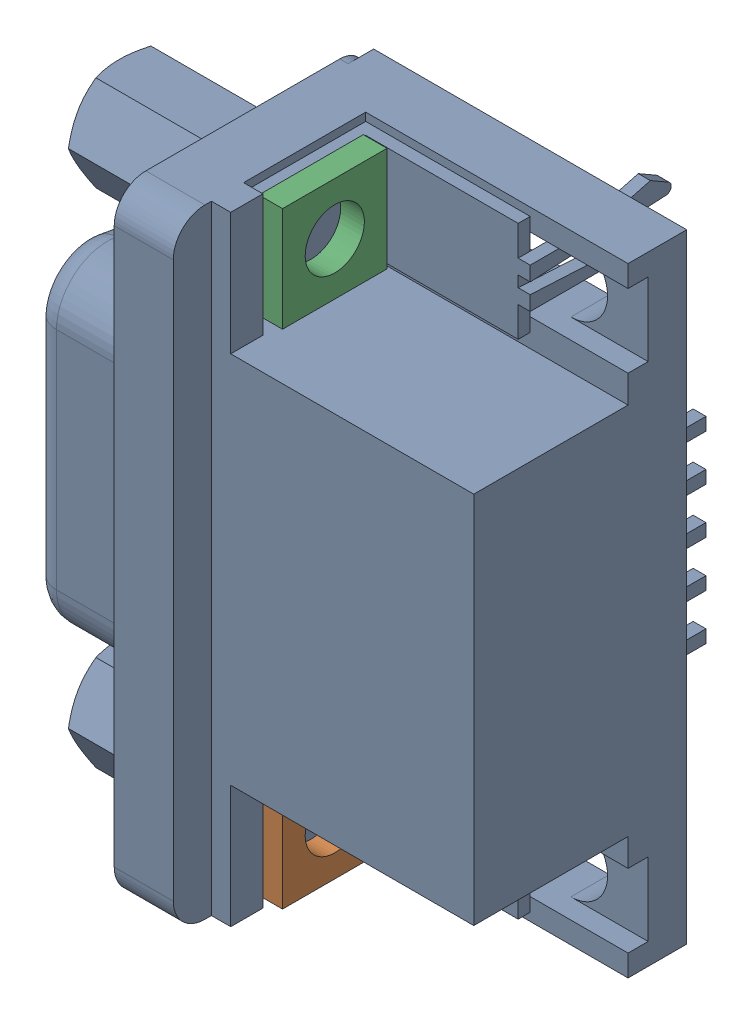
SolidWorks assembly VGA1, configuration Default. Lengths in mm.
Overall size (22.01 30.8 16).
4 component instances, 3 part files, 0 mates.
Components (placement in the parent):
- c-1734344-12-o-3d-1: c-1734344-12-o-3d [Default] at (-3.7586 40.2844 6.5) x (0 -1 0) z (-1 0 0) size (30.8 16 22.01)
  - Open CASCADE STEP translator 6.2 1.85.1.1-1: Open CASCADE STEP translator 6.2 1.85.1.1 [Default] at origin size (30.8 16 22.01)
  - Open CASCADE STEP translator 6.2 1.85.1.2-1: Open CASCADE STEP translator 6.2 1.85.1.2 [Default] at origin size (5.2 5.2 1.18)
  - Open CASCADE STEP translator 6.2 1.85.1.3-1: Open CASCADE STEP translator 6.2 1.85.1.3 [Default] at origin size (5.2 5.2 1.18)
